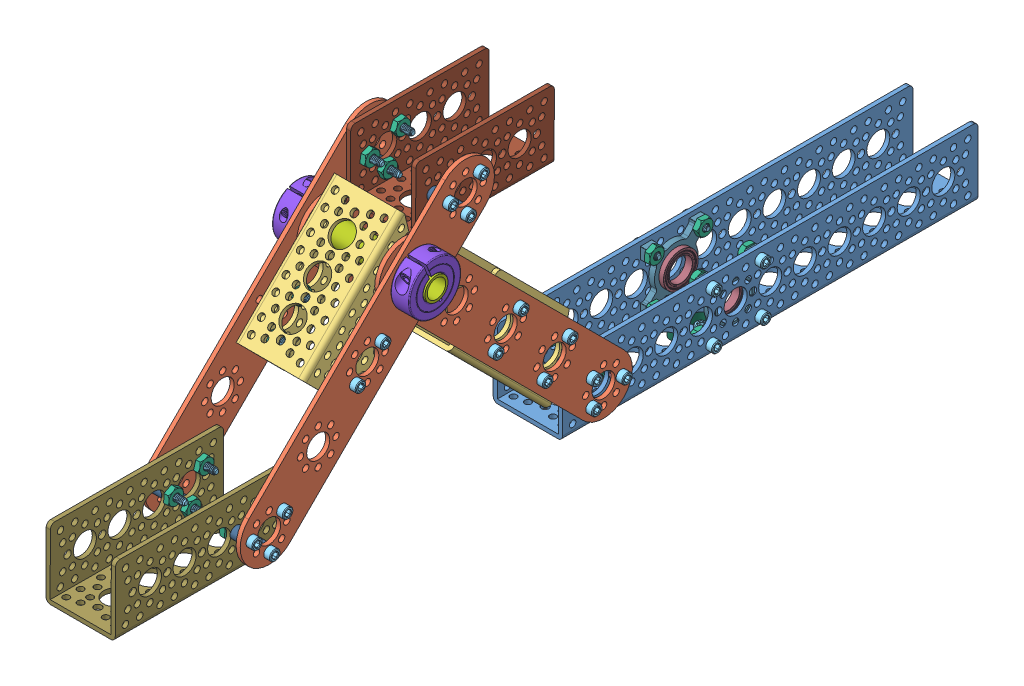
SolidWorks assembly Rocker-Bogie Assembly, configuration Default. Lengths in mm.
Overall size (76.23 183.36 474.66).
136 component instances, 15 part files, 92 mates.
Components (placement in the parent):
- 9 Aluminum Channel-1: 9 Aluminum Channel [Default] at (59.7969 112.1361 56.5133) size (38.1 38.1 228.6)
- Pattern F Bracket-1: Pattern F Bracket [Default] at (58.5269 185.0676 319.9448) x (0 0.707107 0.707107) z (0 -0.707107 0.707107) size (184.15 2.29 31.75)
- 3 Aluminum Channel Mod-1: 3 Aluminum Channel Mod [Default] at (59.7969 131.1861 293.004) x (1 0 0) z (0 0.707107 0.707107) size (38.1 38.1 76.2)
- 6-32 Washer-3: 6-32 Washer [Default] at (58.5269 124.2713 272.9781) x (0 0 -1) z (1 0 0) size (6.35 6.35 1.27)
- 6-32 Washer-6: 6-32 Washer [Default] at (58.5269 178.1528 326.8596) x (0 0 -1) z (1 0 0) size (6.35 6.35 1.27)
- 6-32 Washer-7: 6-32 Washer [Default] at (58.5269 191.9824 313.03) x (0 0 -1) z (1 0 0) size (6.35 6.35 1.27)
- 6-32 Washer-8: 6-32 Washer [Default] at (58.5269 165.0416 286.0892) x (0 -0.924225 -0.381849) z (1 0 0) size (6.35 6.35 1.27)
- 6-32 Washer-9: 6-32 Washer [Default] at (58.5269 151.212 299.9188) x (0 0 -1) z (1 0 0) size (6.35 6.35 1.27)
- 6-32_SHCS-2: 6-32_SHCS [6-32 SHCS X .375] at (65.7659 178.1528 326.8596) x (0 0.924225 0.381849) z (-1 0 0) size (5.74 5.74 13.03)
- 6-32_SHCS-6: 6-32_SHCS [6-32 SHCS X .375] at (65.7659 191.9824 313.03) x (0 0.924225 0.381849) z (-1 0 0) size (5.74 5.74 13.03)
- 6-32_SHCS-7: 6-32_SHCS [6-32 SHCS X .375] at (65.7659 165.0416 286.0892) x (0 0.924225 0.381849) z (-1 0 0) size (5.74 5.74 13.03)
- 6-32_SHCS-8: 6-32_SHCS [6-32 SHCS X .375] at (65.7659 124.2713 272.9781) x (0 0.924225 0.381849) z (-1 0 0) size (5.74 5.74 13.03)
- 6-32_SHCS-9: 6-32_SHCS [6-32 SHCS X .375] at (65.7659 151.212 299.9188) x (0 0 1) z (-1 0 0) size (5.74 5.74 13.03)
- hex_nut-1: hex_nut [#6-32] at (62.0829 191.9824 313.03) x (0 0.381849 -0.924225) z (0 -0.924225 -0.381849) size (7.92 2.9 10.06)
- hex_nut-2: hex_nut [#6-32] at (62.0829 151.212 299.9188) x (0 0.381849 -0.924225) z (0 -0.924225 -0.381849) size (7.92 2.9 10.06)
- hex_nut-3: hex_nut [#6-32] at (62.0829 124.2713 272.9781) x (0 0.381849 -0.924225) z (0 -0.924225 -0.381849) size (7.92 2.9 10.06)
- hex_nut-4: hex_nut [#6-32] at (62.0829 165.0416 286.0892) x (0 -0.870942 -0.491386) z (0 -0.491386 0.870942) size (7.92 2.9 10.06)
- hex_nut-5: hex_nut [#6-32] at (62.0829 178.1528 326.8596) x (0 0.381849 -0.924225) z (0 -0.924225 -0.381849) size (7.92 2.9 10.06)
- hex_nut-10: hex_nut [#6-32] at (62.0829 131.0154 256.2858) x (0 0.399577 0.9167) z (0 0.9167 -0.399577) size (7.92 2.9 10.06)
- hex_nut-11: hex_nut [#6-32] at (62.0829 138.338 272.7325) x (0 -0.936988 -0.349362) z (0 -0.349362 0.936988) size (7.92 2.9 10.06)
- 6-32 Washer-10: 6-32 Washer [Default] at (58.5269 131.0154 256.2858) x (0 0.71934 0.694658) z (1 0 0) size (6.35 6.35 1.27)
- 6-32 Washer-11: 6-32 Washer [Default] at (58.5269 138.338 272.7325) x (0 -0.999391 0.034899) z (1 0 0) size (6.35 6.35 1.27)
- 6-32_SHCS-10: 6-32_SHCS [6-32 SHCS X .375] at (65.7659 131.0154 256.2858) x (0 -0.9167 0.399577) z (-1 0 0) size (5.74 5.74 13.03)
- 6-32_SHCS-11: 6-32_SHCS [6-32 SHCS X .375] at (65.7659 138.338 272.7325) x (0 0.349362 -0.936988) z (-1 0 0) size (5.74 5.74 13.03)
- 3inch Aluminum Rod-1: 3inch Aluminum Rod [Default] at (41.0962 238.9491 373.8263) x (1 0 0) z (0 0.999969 -0.00781) size (76.2 12.7 12.7)
- .5in Collared Clamp-1: .5in Collared Clamp [6157K14] at (46.2556 238.9491 373.8263) x (0 -0.38629 0.922377) z (-1 0 0) size (28.57 28.59 10.38)
- 0.5 Nylon Plastic Washer-1: 0.5 Nylon Plastic Washer [Default] at (53.7009 238.9491 373.8263) x (0 0 -1) z (1 0 0) size (19.05 19.05 1.27)
- 0.5 Nylon Plastic Washer-2: 0.5 Nylon Plastic Washer [Default] at (59.7969 238.9491 373.8263) x (0 0 1) z (-1 0 0) size (19.05 19.05 1.27)
- 0.5 Nylon Plastic Washer-3: 0.5 Nylon Plastic Washer [Default] at (56.2409 238.9491 373.8263) x (0 0 1) z (-1 0 0) size (19.05 19.05 1.27)
- Pattern F Bracket-2: Pattern F Bracket [Default] at (51.4149 212.0953 400.8538) x (0 -0.704825 0.709381) z (0 0.709381 0.704825) size (184.15 2.29 31.75)
- 3 Aluminum Channel Mod-2: 3 Aluminum Channel Mod [Default] at (97.8969 265.8898 373.7396) x (-1 0 0) z (0 -0.704825 0.709381) size (38.1 38.1 76.2)
- 6-32_L0_25 Spacer-1: 6-32_L0_25 Spacer [Default] at (53.7009 205.2028 407.7908) size (6.35 6.35 6.35)
- 6-32_L0_25 Spacer-2: 6-32_L0_25 Spacer [Default] at (53.7009 256.024 346.8304) size (6.35 6.35 6.35)
- 6-32_L0_25 Spacer-4: 6-32_L0_25 Spacer [Default] at (53.7009 148.6087 454.9401) size (6.35 6.35 6.35)
- 6-32_L0_25 Spacer-5: 6-32_L0_25 Spacer [Default] at (53.7009 218.9878 393.9167) size (6.35 6.35 6.35)
- 3 Aluminum Channel-1: 3 Aluminum Channel [Default] at (59.7969 246.569 289.7106) x (1 0 0) z (0 0.003221 0.999995) size (38.1 38.1 76.2)
- 6-32_SHCS-12: 6-32_SHCS [6-32 SHCS X .750] at (70.4649 205.2028 407.7908) x (0 0.924225 0.381849) z (-1 0 0) size (5.74 5.74 22.56)
- 6-32_SHCS-13: 6-32_SHCS [6-32 SHCS X .750] at (70.4649 256.024 346.8304) x (0 0.924225 0.381849) z (-1 0 0) size (5.74 5.74 22.56)
- 6-32_SHCS-15: 6-32_SHCS [6-32 SHCS X .750] at (70.4649 218.9878 393.9167) x (0 0.924225 0.381849) z (-1 0 0) size (5.74 5.74 22.56)
- 6-32_SHCS-16: 6-32_SHCS [6-32 SHCS X .750] at (70.4649 148.6087 454.9401) x (0 0 1) z (-1 0 0) size (5.74 5.74 22.56)
- 3.75 Aluminum Channel-1: 3.75 Aluminum Channel [Default] at (59.7969 139.2763 435.9201) x (1 0 0) z (0 0.003221 0.999995) size (38.1 38.1 95.25)
- hex_nut-12: hex_nut [#6-32] at (62.0829 256.024 346.8304) x (0 0.381849 -0.924225) z (0 -0.924225 -0.381849) size (7.92 2.9 10.06)
- hex_nut-14: hex_nut [#6-32] at (62.0829 218.9878 393.9167) x (0 0.381849 -0.924225) z (0 -0.924225 -0.381849) size (7.92 2.9 10.06)
- hex_nut-15: hex_nut [#6-32] at (62.0829 205.2028 407.7908) x (0 0.381849 -0.924225) z (0 -0.924225 -0.381849) size (7.92 2.9 10.06)
- hex_nut-16: hex_nut [#6-32] at (62.0829 148.6087 454.9401) x (0 -1 0) z (0 0 1) size (7.92 2.9 10.06)
- hex_nut-17: hex_nut [#6-32] at (62.0829 272.5733 339.7427) x (0 0.399577 0.9167) z (0 0.9167 -0.399577) size (7.92 2.9 10.06)
- hex_nut-18: hex_nut [#6-32] at (62.0829 266.1757 356.5708) x (0 -0.936988 -0.349362) z (0 -0.349362 0.936988) size (7.92 2.9 10.06)
- 6-32_L0_25 Spacer-6: 6-32_L0_25 Spacer [Default] at (53.7009 272.5733 339.7427) x (1 0 0) z (0 -0.71934 -0.694658) size (6.35 6.35 6.35)
- 6-32_L0_25 Spacer-7: 6-32_L0_25 Spacer [Default] at (53.7009 266.1757 356.5708) x (1 0 0) z (0 0.999391 -0.034899) size (6.35 6.35 6.35)
- 6-32_SHCS-17: 6-32_SHCS [6-32 SHCS X .750] at (70.4649 272.5733 339.7427) x (0 -0.9167 0.399577) z (-1 0 0) size (5.74 5.74 22.56)
- 6-32_SHCS-18: 6-32_SHCS [6-32 SHCS X .750] at (70.4649 266.1757 356.5708) x (0 0.349362 -0.936988) z (-1 0 0) size (5.74 5.74 22.56)
- hex_nut-19: hex_nut [#6-32] at (62.0829 165.158 447.8523) x (0 0.694658 -0.71934) z (0 -0.71934 -0.694658) size (7.92 2.9 10.06)
- hex_nut-20: hex_nut [#6-32] at (62.0829 158.7604 464.6805) x (0 0.034899 0.999391) z (0 0.999391 -0.034899) size (7.92 2.9 10.06)
- 6-32_L0_25 Spacer-8: 6-32_L0_25 Spacer [Default] at (53.7009 165.158 447.8523) x (1 0 0) z (0 -0.71934 -0.694658) size (6.35 6.35 6.35)
- 6-32_L0_25 Spacer-9: 6-32_L0_25 Spacer [Default] at (53.7009 158.7604 464.6805) x (1 0 0) z (0 0.999391 -0.034899) size (6.35 6.35 6.35)
- 6-32_SHCS-19: 6-32_SHCS [6-32 SHCS X .750] at (70.4649 165.158 447.8523) x (0 -0.71934 -0.694658) z (-1 0 0) size (5.74 5.74 22.56)
- 6-32_SHCS-20: 6-32_SHCS [6-32 SHCS X .750] at (70.4649 158.7604 464.6805) x (0 0.999391 -0.034899) z (-1 0 0) size (5.74 5.74 22.56)
- 6-32_L0_25 Spacer-10: 6-32_L0_25 Spacer [Default] at (103.9929 158.7604 464.6805) x (-1 0 0) z (0 -0.999391 0.034899) size (6.35 6.35 6.35)
- 6-32_SHCS-21: 6-32_SHCS [6-32 SHCS X .750] at (87.2289 158.7604 464.6805) x (0 -0.999391 0.034899) z (1 0 0) size (5.74 5.74 22.56)
- 6-32_SHCS-22: 6-32_SHCS [6-32 SHCS X .750] at (87.2289 148.6087 454.9401) x (0 0 -1) z (1 0 0) size (5.74 5.74 22.56)
- 6-32_L0_25 Spacer-11: 6-32_L0_25 Spacer [Default] at (103.9929 148.6087 454.9401) x (-1 0 0) z (0 0 -1) size (6.35 6.35 6.35)
- 6-32_L0_25 Spacer-12: 6-32_L0_25 Spacer [Default] at (103.9929 165.158 447.8523) x (-1 0 0) z (0 0.71934 0.694658) size (6.35 6.35 6.35)
- 6-32_SHCS-23: 6-32_SHCS [6-32 SHCS X .750] at (87.2289 165.158 447.8523) x (0 0.71934 0.694658) z (1 0 0) size (5.74 5.74 22.56)
- Pattern F Bracket-3: Pattern F Bracket [Default] at (106.2789 212.0953 400.8538) x (0 0.704825 -0.709381) z (0 0.709381 0.704825) size (184.15 2.29 31.75)
- hex_nut-21: hex_nut [#6-32] at (95.6109 148.6087 454.9401) x (0 -1 0) z (0 0 -1) size (7.92 2.9 10.06)
- hex_nut-22: hex_nut [#6-32] at (95.6109 158.7604 464.6805) x (0 0.034899 0.999391) z (0 -0.999391 0.034899) size (7.92 2.9 10.06)
- hex_nut-23: hex_nut [#6-32] at (95.6109 165.158 447.8523) x (0 0.694658 -0.71934) z (0 0.71934 0.694658) size (7.92 2.9 10.06)
- hex_nut-24: hex_nut [#6-32] at (95.6109 205.2028 407.7908) x (0 0.381849 -0.924225) z (0 0.924225 0.381849) size (7.92 2.9 10.06)
- 6-32_SHCS-24: 6-32_SHCS [6-32 SHCS X .750] at (87.2289 205.2028 407.7908) x (0 -0.924225 -0.381849) z (1 0 0) size (5.74 5.74 22.56)
- 6-32_SHCS-25: 6-32_SHCS [6-32 SHCS X .750] at (87.2289 218.9878 393.9167) x (0 -0.924225 -0.381849) z (1 0 0) size (5.74 5.74 22.56)
- hex_nut-25: hex_nut [#6-32] at (95.6109 218.9878 393.9167) x (0 0.381849 -0.924225) z (0 0.924225 0.381849) size (7.92 2.9 10.06)
- .5in Collared Clamp-2: .5in Collared Clamp [6157K14] at (111.4383 238.9491 373.8263) x (0 0.38629 -0.922377) z (1 0 0) size (28.57 28.59 10.38)
- 0.5 Nylon Plastic Washer-4: 0.5 Nylon Plastic Washer [Default] at (102.7229 238.9491 373.8263) x (0 0 -1) z (1 0 0) size (19.05 19.05 1.27)
- 0.5 Nylon Plastic Washer-5: 0.5 Nylon Plastic Washer [Default] at (102.7229 238.9491 373.8263) x (0 0 1) z (-1 0 0) size (19.05 19.05 1.27)
- 0.5 Nylon Plastic Washer-6: 0.5 Nylon Plastic Washer [Default] at (99.1669 238.9491 373.8263) x (0 0 1) z (-1 0 0) size (19.05 19.05 1.27)
- 6-32_L0_25 Spacer-13: 6-32_L0_25 Spacer [Default] at (103.9929 205.2028 407.7908) x (-1 0 0) z (0 0 -1) size (6.35 6.35 6.35)
- 6-32_L0_25 Spacer-14: 6-32_L0_25 Spacer [Default] at (103.9929 218.9878 393.9167) x (-1 0 0) z (0 0 -1) size (6.35 6.35 6.35)
- 6-32_L0_25 Spacer-15: 6-32_L0_25 Spacer [Default] at (103.9929 266.1757 356.5708) x (-1 0 0) z (0 -0.999391 0.034899) size (6.35 6.35 6.35)
- 6-32_L0_25 Spacer-16: 6-32_L0_25 Spacer [Default] at (103.9929 272.5733 339.7427) x (-1 0 0) z (0 0.71934 0.694658) size (6.35 6.35 6.35)
- 6-32_L0_25 Spacer-17: 6-32_L0_25 Spacer [Default] at (103.9929 256.024 346.8304) x (-1 0 0) z (0 0 -1) size (6.35 6.35 6.35)
- 6-32_SHCS-26: 6-32_SHCS [6-32 SHCS X .750] at (87.2289 256.024 346.8304) x (0 -0.924225 -0.381849) z (1 0 0) size (5.74 5.74 22.56)
- 6-32_SHCS-27: 6-32_SHCS [6-32 SHCS X .750] at (87.2289 266.1757 356.5708) x (0 -0.349362 0.936988) z (1 0 0) size (5.74 5.74 22.56)
- 6-32_SHCS-28: 6-32_SHCS [6-32 SHCS X .750] at (87.2289 272.5733 339.7427) x (0 0.9167 -0.399577) z (1 0 0) size (5.74 5.74 22.56)
- 6-32_SHCS-29: 6-32_SHCS [6-32 SHCS X .375] at (91.9279 191.9824 313.03) x (0 -0.924225 -0.381849) z (1 0 0) size (5.74 5.74 13.03)
- 6-32_SHCS-30: 6-32_SHCS [6-32 SHCS X .375] at (91.9279 165.0416 286.0892) x (0 -0.924225 -0.381849) z (1 0 0) size (5.74 5.74 13.03)
- 6-32_SHCS-31: 6-32_SHCS [6-32 SHCS X .375] at (91.9279 131.0154 256.2858) x (0 0.9167 -0.399577) z (1 0 0) size (5.74 5.74 13.03)
- 6-32_SHCS-32: 6-32_SHCS [6-32 SHCS X .375] at (91.9279 138.338 272.7325) x (0 -0.349362 0.936988) z (1 0 0) size (5.74 5.74 13.03)
- 6-32_SHCS-33: 6-32_SHCS [6-32 SHCS X .375] at (91.9279 151.212 299.9188) x (0 0 -1) z (1 0 0) size (5.74 5.74 13.03)
- 6-32_SHCS-34: 6-32_SHCS [6-32 SHCS X .375] at (91.9279 178.1528 326.8596) x (0 -0.924225 -0.381849) z (1 0 0) size (5.74 5.74 13.03)
- 6-32_SHCS-35: 6-32_SHCS [6-32 SHCS X .375] at (91.9279 124.2713 272.9781) x (0 -0.924225 -0.381849) z (1 0 0) size (5.74 5.74 13.03)
- 6-32 Washer-12: 6-32 Washer [Default] at (97.8969 131.0154 256.2858) x (0 0.71934 0.694658) z (1 0 0) size (6.35 6.35 1.27)
- 6-32 Washer-13: 6-32 Washer [Default] at (97.8969 124.2713 272.9781) x (0 0 -1) z (1 0 0) size (6.35 6.35 1.27)
- 6-32 Washer-14: 6-32 Washer [Default] at (97.8969 138.338 272.7325) x (0 -0.999391 0.034899) z (1 0 0) size (6.35 6.35 1.27)
- 6-32 Washer-15: 6-32 Washer [Default] at (97.8969 151.212 299.9188) x (0 0 -1) z (1 0 0) size (6.35 6.35 1.27)
- 6-32 Washer-16: 6-32 Washer [Default] at (97.8969 165.0416 286.0892) x (0 -0.924225 -0.381849) z (1 0 0) size (6.35 6.35 1.27)
- 6-32 Washer-17: 6-32 Washer [Default] at (97.8969 191.9824 313.03) x (0 0 -1) z (1 0 0) size (6.35 6.35 1.27)
- 6-32 Washer-18: 6-32 Washer [Default] at (97.8969 178.1528 326.8596) x (0 0 -1) z (1 0 0) size (6.35 6.35 1.27)
- Pattern F Bracket-4: Pattern F Bracket [Default] at (101.4529 185.0676 319.9448) x (0 -0.707107 -0.707107) z (0 0.707107 -0.707107) size (184.15 2.29 31.75)
- 0.5 Pillow Bearing Block-1: 0.5 Pillow Bearing Block [Default] at (54.9779 139.4622 174.7264) x (0 -0.904025 -0.427479) z (0 -0.427479 0.904025) size (44.3 7.64 44.3)
  - 0.5 Bearing-1: 0.5 Bearing [Default] at (1.0111 10.8528 17.222) size (19.05 3.97 19.05)
  - 0.5 Bearing Block-1: 0.5 Bearing Block [Default] at (1.0111 10.28 17.222) x (-0.904025 0 -0.427479) z (-0.427479 0 0.904025) size (33.27 5.08 33.27)
- 0.5 Pillow Bearing Block-2: 0.5 Pillow Bearing Block [Default] at (102.716 116.0492 198.1394) x (0 -0.427479 -0.904025) z (0 0.904025 -0.427479) size (44.3 7.64 44.3)
  - 0.5 Bearing-1: 0.5 Bearing [Default] at (1.0111 10.8528 17.222) size (19.05 3.97 19.05)
  - 0.5 Bearing Block-1: 0.5 Bearing Block [Default] at (1.0111 10.28 17.222) x (-0.904025 0 -0.427479) z (-0.427479 0 0.904025) size (33.27 5.08 33.27)
- 6-32_SHCS-36: 6-32_SHCS [6-32 SHCS X .375] at (69.3219 144.6564 176.3929) x (0 0.00007 1) z (-1 0 0) size (5.74 5.74 13.03)
- hex_nut-26: hex_nut [#6-32] at (65.2579 144.6564 176.3929) x (0 0.442098 -0.896967) z (0 -0.896967 -0.442098) size (7.92 2.9 10.06)
- 6-32_SHCS-37: 6-32_SHCS [6-32 SHCS X .375] at (69.3219 117.7157 176.3929) x (0 1 -0.00007) z (-1 0 0) size (5.74 5.74 13.03)
- 6-32_SHCS-38: 6-32_SHCS [6-32 SHCS X .375] at (69.3219 117.7157 203.3337) x (0 -0.00007 -1) z (-1 0 0) size (5.74 5.74 13.03)
- 6-32_SHCS-39: 6-32_SHCS [6-32 SHCS X .375] at (69.3219 144.6564 203.3337) x (0 -1 0.00007) z (-1 0 0) size (5.74 5.74 13.03)
- hex_nut-27: hex_nut [#6-32] at (65.2579 117.7157 176.3929) x (0 -0.896967 -0.442098) z (0 -0.442098 0.896967) size (7.92 2.9 10.06)
- hex_nut-28: hex_nut [#6-32] at (65.2579 117.7157 203.3337) x (0 -0.442098 0.896967) z (0 0.896967 0.442098) size (7.92 2.9 10.06)
- hex_nut-29: hex_nut [#6-32] at (65.2579 144.6564 203.3337) x (0 0.896967 0.442098) z (0 0.442098 -0.896967) size (7.92 2.9 10.06)
- 6-32_SHCS-40: 6-32_SHCS [6-32 SHCS X .375] at (88.3719 144.6564 176.3929) x (0 -0.00007 -1) z (1 0 0) size (5.74 5.74 13.03)
- hex_nut-30: hex_nut [#6-32] at (92.4359 144.6564 176.3929) x (0 0.442098 -0.896967) z (0 0.896967 0.442098) size (7.92 2.9 10.06)
- 6-32_SHCS-41: 6-32_SHCS [6-32 SHCS X .375] at (88.3719 117.7157 176.3929) x (0 -1 0.00007) z (1 0 0) size (5.74 5.74 13.03)
- 6-32_SHCS-42: 6-32_SHCS [6-32 SHCS X .375] at (88.3719 117.7157 203.3337) x (0 0.00007 1) z (1 0 0) size (5.74 5.74 13.03)
- 6-32_SHCS-43: 6-32_SHCS [6-32 SHCS X .375] at (88.3719 144.6564 203.3337) x (0 1 -0.00007) z (1 0 0) size (5.74 5.74 13.03)
- hex_nut-31: hex_nut [#6-32] at (92.4359 117.7157 176.3929) x (0 -0.896967 -0.442098) z (0 0.442098 -0.896967) size (7.92 2.9 10.06)
- hex_nut-32: hex_nut [#6-32] at (92.4359 117.7157 203.3337) x (0 -0.442098 0.896967) z (0 -0.896967 -0.442098) size (7.92 2.9 10.06)
- hex_nut-33: hex_nut [#6-32] at (92.4359 144.6564 203.3337) x (0 0.896967 0.442098) z (0 -0.442098 0.896967) size (7.92 2.9 10.06)
- 0.5 Bore Side Tapped Clamping Hub-1: 0.5 Bore Side Tapped Clamping Hub [Default] at (112.3725 93.4655 176.8061) size (20.57 7.21 26.29)
  - 545600-1: 545600 [Default] at (-33.5255 9.1455 13.0572) size (20.57 7.21 26.29)
- 6-32_SHCS-44: 6-32_SHCS [6-32 SHCS X .375] at (71.9322 104.8971 196.7781) x (1 0 0) z (0 1 0) size (5.74 5.74 13.03)
- 6-32_SHCS-45: 6-32_SHCS [6-32 SHCS X .375] at (71.9322 104.8971 182.9485) x (0 0 1) z (0 1 0) size (5.74 5.74 13.03)
- 6-32_SHCS-46: 6-32_SHCS [6-32 SHCS X .375] at (85.7617 104.8971 182.9485) x (-1 0 0) z (0 1 0) size (5.74 5.74 13.03)
- 6-32_SHCS-47: 6-32_SHCS [6-32 SHCS X .375] at (85.7617 104.8971 196.7781) x (0 0 -1) z (0 1 0) size (5.74 5.74 13.03)
- hex_nut-34: hex_nut [#6-32] at (95.6109 165.0416 286.0892) x (0 -0.870942 -0.491386) z (0 0.491386 -0.870942) size (7.92 2.9 10.06)
- hex_nut-35: hex_nut [#6-32] at (95.6109 151.212 299.9188) x (0 0.381849 -0.924225) z (0 0.924225 0.381849) size (7.92 2.9 10.06)
- hex_nut-36: hex_nut [#6-32] at (95.6109 138.338 272.7325) x (0 -0.936988 -0.349362) z (0 0.349362 -0.936988) size (7.92 2.9 10.06)
- hex_nut-37: hex_nut [#6-32] at (95.6109 124.2713 272.9781) x (0 0.381849 -0.924225) z (0 0.924225 0.381849) size (7.92 2.9 10.06)
- hex_nut-38: hex_nut [#6-32] at (95.6109 131.0154 256.2858) x (0 0.399577 0.9167) z (0 -0.9167 0.399577) size (7.92 2.9 10.06)
- hex_nut-39: hex_nut [#6-32] at (95.6109 191.9824 313.03) x (0 0.381849 -0.924225) z (0 0.924225 0.381849) size (7.92 2.9 10.06)
- hex_nut-40: hex_nut [#6-32] at (95.6109 178.1528 326.8596) x (0 0.381849 -0.924225) z (0 0.924225 0.381849) size (7.92 2.9 10.06)
- hex_nut-41: hex_nut [#6-32] at (95.6109 266.1757 356.5708) x (0 -0.936988 -0.349362) z (0 0.349362 -0.936988) size (7.92 2.9 10.06)
- hex_nut-42: hex_nut [#6-32] at (95.6109 272.5733 339.7427) x (0 0.399577 0.9167) z (0 -0.9167 0.399577) size (7.92 2.9 10.06)
- hex_nut-43: hex_nut [#6-32] at (95.6109 256.024 346.8304) x (0 0.381849 -0.924225) z (0 0.924225 0.381849) size (7.92 2.9 10.06)
Mates (geometry in assembly coordinates):
- Concentric1: concentric aligned: cylinder of 9 Aluminum Channel-1 through (97.8969 124.2713 272.9781) axis (1 0 0) radius 1.778; cylinder of 6-32_SHCS-8 through (43.5409 124.2713 272.9781) axis (1 0 0) radius 2.8702
- Concentric2: concentric anti-aligned: cylinder of 9 Aluminum Channel-1 through (97.8969 124.2713 272.9781) axis (1 0 0) radius 1.778; cylinder of 6-32 Washer-3 through (59.7969 124.2713 272.9781) axis (-1 0 0) radius 3.175
- Concentric3: concentric aligned: cylinder of 9 Aluminum Channel-1 through (97.8969 124.2713 272.9781) axis (1 0 0) radius 1.778; cylinder of hex_nut-3 through (62.159 124.2713 272.9781) axis (1 0 0) radius 1.323
- Concentric4: concentric aligned: cylinder of 3 Aluminum Channel Mod-1 through (97.8969 151.212 299.9188) axis (1 0 0) radius 1.778; cylinder of 6-32_SHCS-9 through (43.5409 151.212 299.9188) axis (1 0 0) radius 2.8702
- Concentric5: concentric anti-aligned: cylinder of 3 Aluminum Channel Mod-1 through (97.8969 151.212 299.9188) axis (1 0 0) radius 1.778; cylinder of 6-32 Washer-9 through (59.7969 151.212 299.9188) axis (-1 0 0) radius 3.175
- Concentric6: concentric aligned: cylinder of 3 Aluminum Channel Mod-1 through (97.8969 151.212 299.9188) axis (1 0 0) radius 1.778; cylinder of hex_nut-2 through (62.159 151.212 299.9188) axis (1 0 0) radius 1.323
- Concentric7: concentric aligned: cylinder of 3 Aluminum Channel Mod-1 through (97.8969 165.0416 286.0892) axis (1 0 0) radius 1.778; cylinder of 6-32_SHCS-7 through (43.5409 165.0416 286.0892) axis (1 0 0) radius 2.8702
- Concentric8: concentric anti-aligned: circle of hex_nut-4; cylinder of 6-32 Washer-8 through (59.7969 165.0416 286.0892) axis (-1 0 0) radius 3.175
- Concentric9: concentric aligned: circle of hex_nut-4; cylinder of 3 Aluminum Channel Mod-1 through (97.8969 165.0416 286.0892) axis (1 0 0) radius 1.778
- Concentric10: concentric anti-aligned: cylinder of 3 Aluminum Channel Mod-1 through (97.8969 191.9824 313.03) axis (1 0 0) radius 1.778; cylinder of 6-32 Washer-7 through (59.7969 191.9824 313.03) axis (-1 0 0) radius 3.175
- Concentric11: concentric aligned: cylinder of 3 Aluminum Channel Mod-1 through (97.8969 191.9824 313.03) axis (1 0 0) radius 1.778; cylinder of 6-32_SHCS-6 through (43.5409 191.9824 313.03) axis (1 0 0) radius 2.8702
- Concentric12: concentric aligned: cylinder of 3 Aluminum Channel Mod-1 through (97.8969 191.9824 313.03) axis (1 0 0) radius 1.778; cylinder of hex_nut-1 through (62.159 191.9824 313.03) axis (1 0 0) radius 1.323
- Concentric13: concentric anti-aligned: cylinder of 3 Aluminum Channel Mod-1 through (97.8969 178.1528 326.8596) axis (1 0 0) radius 1.778; cylinder of 6-32 Washer-6 through (59.7969 178.1528 326.8596) axis (-1 0 0) radius 3.175
- Concentric14: concentric aligned: cylinder of 3 Aluminum Channel Mod-1 through (97.8969 178.1528 326.8596) axis (1 0 0) radius 1.778; cylinder of 6-32_SHCS-2 through (43.5409 178.1528 326.8596) axis (1 0 0) radius 2.8702
- Concentric15: concentric aligned: cylinder of 3 Aluminum Channel Mod-1 through (97.8969 178.1528 326.8596) axis (1 0 0) radius 1.778; cylinder of hex_nut-5 through (62.159 178.1528 326.8596) axis (1 0 0) radius 1.323
- Coincident1: coincident aligned: plane of 9 Aluminum Channel-1 through (59.7969 112.1361 285.1133) normal (-1 0 0); plane of 3 Aluminum Channel Mod-1 through (59.7969 185.0676 346.8856) normal (-1 0 0)
- Coincident2: coincident anti-aligned: plane of 9 Aluminum Channel-1 through (59.7969 112.1361 285.1133) normal (-1 0 0); plane of 6-32 Washer-3 through (59.7969 124.2713 272.9781) normal (1 0 0)
- Coincident3: coincident anti-aligned: plane of 9 Aluminum Channel-1 through (59.7969 112.1361 285.1133) normal (-1 0 0); plane of 6-32 Washer-9 through (59.7969 151.212 299.9188) normal (1 0 0)
- Coincident5: coincident anti-aligned: plane of 9 Aluminum Channel-1 through (59.7969 112.1361 285.1133) normal (-1 0 0); plane of 6-32 Washer-7 through (59.7969 191.9824 313.03) normal (1 0 0)
- Coincident6: coincident anti-aligned: plane of 9 Aluminum Channel-1 through (59.7969 112.1361 285.1133) normal (-1 0 0); plane of 6-32 Washer-6 through (59.7969 178.1528 326.8596) normal (1 0 0)
- Coincident7: coincident anti-aligned: plane of 9 Aluminum Channel-1 through (59.7969 112.1361 285.1133) normal (-1 0 0); plane of 6-32 Washer-8 through (59.7969 165.0416 286.0892) normal (1 0 0)
- Coincident8: coincident anti-aligned: plane of Pattern F Bracket-1 through (58.5269 131.1861 266.0633) normal (1 0 0); plane of 6-32 Washer-3 through (58.5269 124.2713 272.9781) normal (-1 0 0)
- Concentric16: concentric anti-aligned: cylinder of 9 Aluminum Channel-1 through (97.8969 131.1861 266.0633) axis (1 0 0) radius 6.3627; cylinder of Pattern F Bracket-1 through (56.2409 131.1861 266.0633) axis (-1 0 0) radius 6.3627
- Concentric17: concentric anti-aligned: cylinder of 9 Aluminum Channel-1 through (97.8969 124.2713 272.9781) axis (1 0 0) radius 1.778; cylinder of Pattern F Bracket-1 through (56.2409 124.2713 272.9781) axis (-1 0 0) radius 1.778
- Coincident9: coincident anti-aligned: plane of Pattern F Bracket-1 through (56.2409 131.1861 266.0633) normal (-1 0 0); plane of 6-32_SHCS-8 through (56.2409 124.2713 272.9781) normal (1 0 0)
- Coincident10: coincident anti-aligned: plane of Pattern F Bracket-1 through (56.2409 131.1861 266.0633) normal (-1 0 0); plane of 6-32_SHCS-7 through (56.2409 165.0416 286.0892) normal (1 0 0)
- Coincident11: coincident anti-aligned: plane of Pattern F Bracket-1 through (56.2409 131.1861 266.0633) normal (-1 0 0); plane of 6-32_SHCS-9 through (56.2409 151.212 299.9188) normal (1 0 0)
- Coincident12: coincident anti-aligned: plane of Pattern F Bracket-1 through (56.2409 131.1861 266.0633) normal (-1 0 0); plane of 6-32_SHCS-6 through (56.2409 191.9824 313.03) normal (1 0 0)
- Coincident13: coincident anti-aligned: plane of Pattern F Bracket-1 through (56.2409 131.1861 266.0633) normal (-1 0 0); plane of 6-32_SHCS-2 through (56.2409 178.1528 326.8596) normal (1 0 0)
- Concentric18: concentric anti-aligned: cylinder of Pattern F Bracket-1 through (56.2409 158.1268 293.004) axis (-1 0 0) radius 6.3627; cylinder of 3 Aluminum Channel Mod-1 through (97.8969 158.1268 293.004) axis (1 0 0) radius 6.3627
- Concentric19: concentric anti-aligned: cylinder of Pattern F Bracket-1 through (56.2409 185.0676 319.9448) axis (-1 0 0) radius 6.3627; cylinder of 3 Aluminum Channel Mod-1 through (97.8969 185.0676 319.9448) axis (1 0 0) radius 6.3627
- Coincident14: coincident anti-aligned: plane of 9 Aluminum Channel-1 through (62.0829 150.2361 285.1133) normal (1 0 0); plane of hex_nut-3 through (62.0829 129.1012 279.2609) normal (-1 0 0)
- Coincident15: coincident anti-aligned: plane of 9 Aluminum Channel-1 through (62.0829 150.2361 285.1133) normal (1 0 0); plane of hex_nut-2 through (62.0829 156.042 306.2016) normal (-1 0 0)
- Coincident16: coincident anti-aligned: plane of 9 Aluminum Channel-1 through (62.0829 150.2361 285.1133) normal (1 0 0); plane of hex_nut-4 through (62.0829 171.8651 282.059) normal (-1 0 0)
- Coincident17: coincident anti-aligned: plane of 9 Aluminum Channel-1 through (62.0829 150.2361 285.1133) normal (1 0 0); plane of hex_nut-5 through (62.0829 182.9828 333.1424) normal (-1 0 0)
- Coincident18: coincident anti-aligned: plane of 9 Aluminum Channel-1 through (62.0829 150.2361 285.1133) normal (1 0 0); plane of hex_nut-1 through (62.0829 196.8124 319.3128) normal (-1 0 0)
- Concentric20: concentric anti-aligned: cylinder of Pattern F Bracket-1 through (56.2409 238.9491 373.8263) axis (-1 0 0) radius 6.3627; circle of 0.5 Nylon Plastic Washer-1
- Concentric21: concentric anti-aligned: cylinder of Pattern F Bracket-1 through (56.2409 238.9491 373.8263) axis (-1 0 0) radius 6.3627; cylinder of 0.5 Nylon Plastic Washer-3 through (54.9709 238.9491 373.8263) axis (1 0 0) radius 6.35
- Concentric22: concentric anti-aligned: cylinder of Pattern F Bracket-1 through (56.2409 238.9491 373.8263) axis (-1 0 0) radius 6.3627; cylinder of 0.5 Nylon Plastic Washer-2 through (58.5269 238.9491 373.8263) axis (1 0 0) radius 6.35
- Concentric23: concentric aligned: cylinder of Pattern F Bracket-1 through (56.2409 238.9491 373.8263) axis (-1 0 0) radius 6.3627; cylinder of 3inch Aluminum Rod-1 through (117.2962 238.9491 373.8263) axis (-1 0 0) radius 6.35
- Concentric24: concentric anti-aligned: cylinder of Pattern F Bracket-1 through (56.2409 238.9491 373.8263) axis (-1 0 0) radius 6.3627; cylinder of .5in Collared Clamp-1 through (41.0962 238.9491 373.8263) axis (1 0 0) radius 6.35
- Concentric25: concentric anti-aligned: cylinder of Pattern F Bracket-1 through (56.2409 238.9491 373.8263) axis (-1 0 0) radius 6.3627; cylinder of Pattern F Bracket-2 through (53.7009 238.9491 373.8263) axis (1 0 0) radius 6.3627
- Concentric26: concentric aligned: cylinder of 3inch Aluminum Rod-1 through (117.2962 238.9491 373.8263) axis (-1 0 0) radius 6.35; cylinder of 3 Aluminum Channel Mod-2 through (59.7969 238.9491 373.8263) axis (-1 0 0) radius 6.3627
- Coincident19: coincident anti-aligned: plane of 0.5 Nylon Plastic Washer-2 through (59.7969 238.9491 373.8263) normal (1 0 0); plane of 3 Aluminum Channel Mod-2 through (59.7969 185.1547 400.9405) normal (-1 0 0)
- Coincident20: coincident anti-aligned: plane of Pattern F Bracket-1 through (58.5269 131.1861 266.0633) normal (1 0 0); plane of 0.5 Nylon Plastic Washer-2 through (58.5269 238.9491 373.8263) normal (-1 0 0)
- Coincident21: coincident anti-aligned: plane of 0.5 Nylon Plastic Washer-1 through (54.9709 238.9491 373.8263) normal (1 0 0); plane of 0.5 Nylon Plastic Washer-3 through (54.9709 238.9491 373.8263) normal (-1 0 0)
- Coincident22: coincident anti-aligned: plane of Pattern F Bracket-1 through (56.2409 131.1861 266.0633) normal (-1 0 0); plane of 0.5 Nylon Plastic Washer-3 through (56.2409 238.9491 373.8263) normal (1 0 0)
- Coincident23: coincident anti-aligned: plane of 0.5 Nylon Plastic Washer-1 through (53.7009 238.9491 373.8263) normal (-1 0 0); plane of Pattern F Bracket-2 through (53.7009 265.803 346.7989) normal (1 0 0)
- Coincident24: coincident anti-aligned: plane of .5in Collared Clamp-1 through (51.4149 238.9491 373.8263) normal (1 0 0); plane of Pattern F Bracket-2 through (51.4149 265.803 346.7989) normal (-1 0 0)
- Concentric31: concentric anti-aligned: cylinder of Pattern F Bracket-2 through (53.7009 205.1582 393.9613) axis (1 0 0) radius 1.778; cylinder of 3 Aluminum Channel Mod-2 through (59.7969 205.1582 393.9613) axis (-1 0 0) radius 1.778
- Concentric32: concentric aligned: cylinder of 6-32_L0_25 Spacer-5 through (53.7009 218.9878 393.9167) axis (1 0 0) radius 1.651; cylinder of Pattern F Bracket-2 through (53.7009 218.9878 393.9167) axis (1 0 0) radius 1.778
- Concentric33: concentric aligned: cylinder of 6-32_L0_25 Spacer-5 through (53.7009 218.9878 393.9167) axis (1 0 0) radius 1.651; cylinder of hex_nut-14 through (62.159 218.9878 393.9167) axis (1 0 0) radius 1.323
- Concentric34: concentric aligned: cylinder of 6-32_L0_25 Spacer-5 through (53.7009 218.9878 393.9167) axis (1 0 0) radius 1.651; cylinder of 6-32_SHCS-15 through (38.7149 218.9878 393.9167) axis (1 0 0) radius 2.8702
- Concentric35: concentric anti-aligned: cylinder of Pattern F Bracket-2 through (53.7009 205.2028 407.7908) axis (1 0 0) radius 1.778; cylinder of 6-32_L0_25 Spacer-1 through (60.0509 205.2028 407.7908) axis (-1 0 0) radius 3.175
- Concentric36: concentric aligned: cylinder of Pattern F Bracket-2 through (53.7009 205.2028 407.7908) axis (1 0 0) radius 1.778; cylinder of hex_nut-15 through (62.159 205.2028 407.7908) axis (1 0 0) radius 1.323
- Concentric37: concentric aligned: cylinder of Pattern F Bracket-2 through (53.7009 205.2028 407.7908) axis (1 0 0) radius 1.778; cylinder of 6-32_SHCS-12 through (38.7149 205.2028 407.7908) axis (1 0 0) radius 2.8702
- Concentric38: concentric aligned: cylinder of Pattern F Bracket-2 through (53.7009 158.3876 454.9086) axis (1 0 0) radius 6.3627; cylinder of 3.75 Aluminum Channel-1 through (97.8969 158.3876 454.9086) axis (1 0 0) radius 6.3627
- Concentric39: concentric aligned: cylinder of Pattern F Bracket-2 through (53.7009 148.6087 454.9401) axis (1 0 0) radius 1.778; cylinder of 3.75 Aluminum Channel-1 through (97.8969 148.6087 454.9401) axis (1 0 0) radius 1.778
- Concentric40: concentric anti-aligned: cylinder of 6-32_L0_25 Spacer-4 through (60.0509 148.6087 454.9401) axis (-1 0 0) radius 3.175; cylinder of Pattern F Bracket-2 through (53.7009 148.6087 454.9401) axis (1 0 0) radius 1.778
- Concentric41: concentric anti-aligned: cylinder of 6-32_L0_25 Spacer-4 through (60.0509 148.6087 454.9401) axis (-1 0 0) radius 3.175; cylinder of 6-32_SHCS-16 through (38.7149 148.6087 454.9401) axis (1 0 0) radius 2.8702
- Concentric42: concentric anti-aligned: cylinder of 6-32_L0_25 Spacer-4 through (60.0509 148.6087 454.9401) axis (-1 0 0) radius 3.175; cylinder of hex_nut-16 through (62.159 148.6087 454.9401) axis (1 0 0) radius 1.323
- Coincident28: coincident aligned: plane of 3.75 Aluminum Channel-1 through (59.7969 139.5832 531.1696) normal (-1 0 0); plane of 9 Aluminum Channel-1 through (59.7969 112.1361 285.1133) normal (-1 0 0)
- Coincident29: coincident aligned: plane of 3.75 Aluminum Channel-1 through (59.7969 139.5832 531.1696) normal (-1 0 0); plane of 3 Aluminum Channel-1 through (59.7969 246.8144 365.9102) normal (-1 0 0)
- Concentric43: concentric aligned: cylinder of Pattern F Bracket-2 through (53.7009 265.803 346.7989) axis (1 0 0) radius 6.3627; cylinder of 3 Aluminum Channel-1 through (97.8969 265.803 346.7989) axis (1 0 0) radius 6.3627
- Concentric44: concentric aligned: cylinder of Pattern F Bracket-2 through (53.7009 256.024 346.8304) axis (1 0 0) radius 1.778; cylinder of 3 Aluminum Channel-1 through (97.8969 256.024 346.8304) axis (1 0 0) radius 1.778
- Concentric45: concentric anti-aligned: cylinder of Pattern F Bracket-2 through (53.7009 256.024 346.8304) axis (1 0 0) radius 1.778; cylinder of 6-32_L0_25 Spacer-2 through (60.0509 256.024 346.8304) axis (-1 0 0) radius 3.175
- Concentric46: concentric aligned: cylinder of Pattern F Bracket-2 through (53.7009 256.024 346.8304) axis (1 0 0) radius 1.778; cylinder of 6-32_SHCS-13 through (38.7149 256.024 346.8304) axis (1 0 0) radius 2.8702
- Concentric47: concentric aligned: cylinder of Pattern F Bracket-2 through (53.7009 256.024 346.8304) axis (1 0 0) radius 1.778; cylinder of hex_nut-12 through (62.159 256.024 346.8304) axis (1 0 0) radius 1.323
- Coincident30: coincident anti-aligned: plane of Pattern F Bracket-2 through (51.4149 265.803 346.7989) normal (-1 0 0); plane of 6-32_SHCS-12 through (51.4149 205.2028 407.7908) normal (1 0 0)
- Coincident31: coincident anti-aligned: plane of Pattern F Bracket-2 through (51.4149 265.803 346.7989) normal (-1 0 0); plane of 6-32_SHCS-15 through (51.4149 218.9878 393.9167) normal (1 0 0)
- Coincident32: coincident anti-aligned: plane of Pattern F Bracket-2 through (51.4149 265.803 346.7989) normal (-1 0 0); plane of 6-32_SHCS-13 through (51.4149 256.024 346.8304) normal (1 0 0)
- Coincident33: coincident anti-aligned: plane of Pattern F Bracket-2 through (51.4149 265.803 346.7989) normal (-1 0 0); plane of 6-32_SHCS-16 through (51.4149 148.6087 454.9401) normal (1 0 0)
- Coincident34: coincident anti-aligned: plane of 3.75 Aluminum Channel-1 through (62.0829 177.683 531.0468) normal (1 0 0); plane of hex_nut-16 through (62.0829 152.5711 448.077) normal (-1 0 0)
- Coincident35: coincident anti-aligned: plane of 3.75 Aluminum Channel-1 through (62.0829 177.683 531.0468) normal (1 0 0); plane of hex_nut-15 through (62.0829 210.0328 414.0736) normal (-1 0 0)
- Coincident36: coincident anti-aligned: plane of 3.75 Aluminum Channel-1 through (62.0829 177.683 531.0468) normal (1 0 0); plane of hex_nut-14 through (62.0829 223.8178 400.1995) normal (-1 0 0)
- Coincident37: coincident anti-aligned: plane of 3.75 Aluminum Channel-1 through (62.0829 177.683 531.0468) normal (1 0 0); plane of hex_nut-12 through (62.0829 260.854 353.1132) normal (-1 0 0)
- Concentric48: concentric anti-aligned: cylinder of 0.5 Pillow Bearing Block-1/0.5 Bearing-1 through (67.8151 131.1861 189.8633) axis (-1 0 0) radius 6.35; cylinder of 0.5 Pillow Bearing Block-2/0.5 Bearing-1 through (89.8788 131.1861 189.8633) axis (1 0 0) radius 6.35
- Concentric49: concentric anti-aligned: cylinder of 0.5 Pillow Bearing Block-1/0.5 Bearing-1 through (67.8151 131.1861 189.8633) axis (-1 0 0) radius 6.35; cylinder of 9 Aluminum Channel-1 through (97.8969 131.1861 189.8633) axis (1 0 0) radius 6.3627
- Concentric50: concentric aligned: cylinder of 6-32_SHCS-36 through (47.0969 144.6564 176.3929) axis (1 0 0) radius 2.8702; cylinder of 9 Aluminum Channel-1 through (97.8969 144.6564 176.3929) axis (1 0 0) radius 1.778
- Concentric51: concentric aligned: cylinder of 6-32_SHCS-36 through (47.0969 144.6564 176.3929) axis (1 0 0) radius 2.8702; cylinder of hex_nut-26 through (66.9215 144.6564 176.3929) axis (1 0 0) radius 1.323
- Coincident46: coincident aligned: plane of 9 Aluminum Channel-1 through (59.7969 112.1361 285.1133) normal (-1 0 0); circle of 6-32_SHCS-36
- Concentric53: concentric aligned: cylinder of 9 Aluminum Channel-1 through (78.8469 112.1361 189.8633) axis (0 -1 0) radius 6.3627; cylinder of 0.5 Bore Side Tapped Clamping Hub-1/545600-1 through (78.8469 102.6111 189.8633) axis (0 -1 0) radius 6.35
- Concentric54: concentric aligned: cylinder of 6-32_SHCS-44 through (71.9322 127.1221 196.7781) axis (0 -1 0) radius 2.8702; cylinder of 9 Aluminum Channel-1 through (71.9322 112.1361 196.7781) axis (0 -1 0) radius 1.778
- Concentric55: concentric aligned: cylinder of 6-32_SHCS-44 through (71.9322 127.1221 196.7781) axis (0 -1 0) radius 2.8702; cylinder of 0.5 Bore Side Tapped Clamping Hub-1/545600-1 through (71.9322 114.0479 196.7781) axis (0 -1 0) radius 1.7526
- Coincident47: coincident anti-aligned: plane of 9 Aluminum Channel-1 through (97.8969 112.1361 285.1133) normal (0 -1 0); plane of 0.5 Bore Side Tapped Clamping Hub-1/545600-1 through (78.8469 112.1361 189.8633) normal (0 1 0)
- Coincident48: coincident anti-aligned: plane of 9 Aluminum Channel-1 through (62.0829 114.4221 285.1133) normal (0 1 0); plane of 6-32_SHCS-44 through (71.9322 114.4221 196.7781) normal (0 -1 0)
- Concentric56: concentric anti-aligned: cylinder of 0.5 Pillow Bearing Block-2/0.5 Bearing Block-1 through (95.6109 144.6564 203.3337) axis (1 0 0) radius 1.778; cylinder of 6-32_SHCS-43 through (110.5969 144.6564 203.3337) axis (-1 0 0) radius 2.8702
- Concentric57: concentric anti-aligned: cylinder of 0.5 Pillow Bearing Block-1/0.5 Bearing Block-1 through (62.0829 144.6564 203.3337) axis (-1 0 0) radius 1.778; cylinder of 6-32_SHCS-39 through (47.0969 144.6564 203.3337) axis (1 0 0) radius 2.8702
- Coincident49: coincident aligned: plane of 3inch Aluminum Rod-1 through (41.0962 238.9491 373.8263) normal (-1 0 0); plane of .5in Collared Clamp-1 through (41.0962 238.9491 373.8263) normal (-1 0 0)
- Coincident50: coincident anti-aligned: plane of 9 Aluminum Channel-1 through (62.0829 150.2361 285.1133) normal (1 0 0); plane of 0.5 Pillow Bearing Block-1/0.5 Bearing Block-1 through (62.0829 131.1861 189.8633) normal (-1 0 0)
- Coincident51: coincident anti-aligned: plane of 9 Aluminum Channel-1 through (95.6109 114.4221 285.1133) normal (-1 0 0); plane of 0.5 Pillow Bearing Block-2/0.5 Bearing Block-1 through (95.6109 131.1861 189.8633) normal (1 0 0)
- Coincident52: coincident anti-aligned: plane of 0.5 Pillow Bearing Block-1/0.5 Bearing Block-1 through (65.2579 131.1861 189.8633) normal (1 0 0); plane of hex_nut-29 through (65.2579 138.0681 207.7378) normal (-1 0 0)
